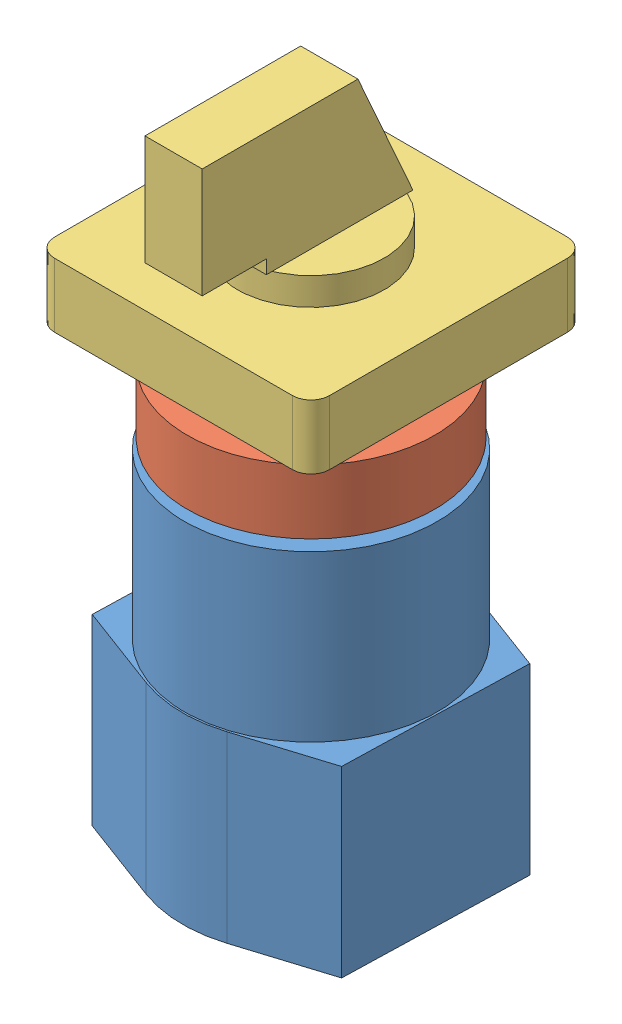
SolidWorks assembly Kraus-Naimer-CG4-A220-600FS2, configuration Default. Lengths in mm.
Overall size (38.05 73.5 38.05).
3 component instances, 3 part files, 7 mates.
Components (placement in the parent):
- Switch_Base^Kraus-Naimer-CG4-A220-600FS2-1: Switch_Base^Kraus-Naimer-CG4-A220-600FS2 [Default] at (-14.2688 -30 9.6126) x (0.999624 0 0.027406) z (-0.027406 0 0.999624) size (28 38 28) (virtual)
- Switch_Locknut^Kraus-Naimer-CG4-A220-600FS2-1: Switch_Locknut^Kraus-Naimer-CG4-A220-600FS2 [Default] at (0 -11 0) x (-0.645743 0 -0.763555) z (0.763555 0 -0.645743) size (27 7 27) (virtual)
- Switch_Top^Kraus-Naimer-CG4-A220-600FS2-1: Switch_Top^Kraus-Naimer-CG4-A220-600FS2 [Default] at origin size (30 54.5 30) (virtual)
Mates (geometry in assembly coordinates):
- Concentric1: concentric anti-aligned: cylinder of Copy of Switch_Base^CG4-1 through (0 -27 0) axis (0 1 0) radius 3; cylinder of Switch_Locknut^CG4-1 through (0 -4 0) axis (0 -1 0) radius 8
- Concentric2: concentric aligned: cylinder of Copy of Switch_Base^CG4-1 through (0 -27 0) axis (0 1 0) radius 3; cylinder of Switch_Top^CG4-1 through (0 -31 0) axis (0 1 0) radius 2.5
- LimitDistance1: limit distance = 4 mm anti-aligned: plane of Switch_Locknut^CG4-1 through (0 -4 0) normal (0 1 0); plane of Switch_Top^CG4-1 through (0 0 0) normal (0 -1 0)
- Distance2: distance = 12 mm anti-aligned: plane of Switch_Top^CG4-1 through (0 0 0) normal (0 -1 0); plane of Switch_Base^CG4-1 through (0 -12 0) normal (0 1 0)
- Coincident1: coincident anti-aligned: plane of Switch_Top^Kraus-Naimer-CG4-A220-600FS2-1 through (0 0 0) normal (0 -1 0)
- Coincident2: coincident aligned: plane of Switch_Top^Kraus-Naimer-CG4-A220-600FS2-1 through (0 0 0) normal (0 0 1)
- Coincident3: coincident aligned: plane of Switch_Top^Kraus-Naimer-CG4-A220-600FS2-1 through (0 0 0) normal (1 0 0)
